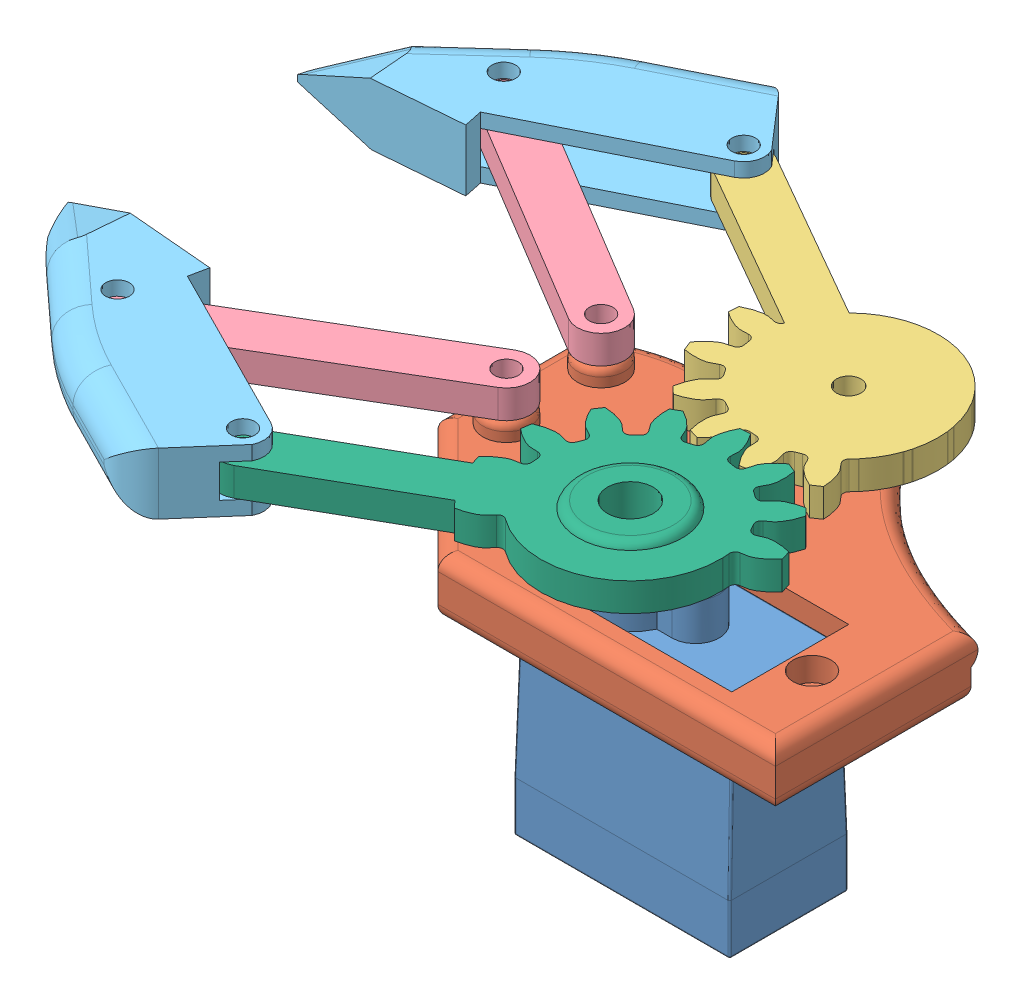
SolidWorks assembly GripperAssemV1, configuration Default. Lengths in mm.
Overall size (86.94 31.5 72.29).
8 component instances, 6 part files, 19 mates.
Components (placement in the parent):
- Part1-1: Part1 [Default] at (2.8598 15.8035 31.9584) size (32.1 26.81 12.5)
- BaseV4Part1-1: BaseV4Part1 [Default] at (7.8348 24.1035 14.5584) x (0 0 1) z (-1 0 0) size (38.46 8 48.6)
- RightGearPart2-1: RightGearPart2 [Default] at (13.6898 28.6035 -7.4143) x (0.4976 0 -0.867406) z (-0.867406 0 -0.4976) size (22.37 3 44.56)
- ShortHandPart4-1: ShortHandPart4 [Default] at (-49.9817 26.6035 -19.7668) x (0.514522 0 -0.857477) z (0.857477 0 0.514522) size (5 3 35)
- ShortHandPart4-2: ShortHandPart4 [Default] at (7.7756 26.6035 14.3423) x (0.509964 0 0.860195) z (-0.860195 0 0.509964) size (5 3 35)
- GripperHeadV4Part5-1: GripperHeadV4Part5 [Default] at (-14.2358 27.4535 -10.8856) x (-0.447199 0 -0.894435) z (0 1 0) size (13.93 38 6.5)
- ServoGearPart3-1: ServoGearPart3 [Default] at (2.1903 26.4035 16.5668) x (0.495746 0 0.868468) z (-0.868468 0 0.495746) size (22.59 3.7 45.43)
- GripperHeadV4Part5-2: GripperHeadV4Part5 [Default] at (-14.3385 27.8535 39.9593) x (-0.450943 0 0.892553) z (0 -1 0) size (13.93 38 6.5)
Mates (geometry in assembly coordinates):
- Coincident12: coincident: plane of Part1-1 through (-1.9402 18.1035 19.8084) normal (0 1 0); plane of BaseV4Part1-1 through (7.8348 18.1035 14.5584) normal (0 -1 0)
- Concentric5: concentric: circle of Part1-1; circle of BaseV4Part1-1
- Parallel11: parallel: plane of Part1-1 through (30.1598 22.2035 31.9584) normal (0 0 1); plane of BaseV4Part1-1 through (2.6548 21.1035 32.2384) normal (0 0 -1)
- Concentric14: concentric: cylinder of BaseV4Part1-1 through (8.8348 24.1035 3.0584) axis (0 1 0) radius 1.3; cylinder of RightGearPart2-1 through (8.8348 29.1035 3.0584) axis (0 -1 0) radius 1.3
- Coincident15: coincident: circle of BaseV4Part1-1; plane of RightGearPart2-1 through (-17.1874 26.1035 -11.8696) normal (0 -1 0)
- Concentric15: concentric: cylinder of BaseV4Part1-1 through (-10.8275 18.1035 9.5584) axis (0 1 0) radius 1.25; cylinder of ShortHandPart4-1 through (-10.8275 29.1035 9.5584) axis (0 -1 0) radius 1.25
- Coincident16: coincident: circle of BaseV4Part1-1; plane of ShortHandPart4-1 through (-10.8275 26.1035 9.5584) normal (0 -1 0)
- Concentric17: concentric: cylinder of BaseV4Part1-1 through (-10.8275 18.1035 19.5584) axis (0 1 0) radius 1.25; cylinder of ShortHandPart4-2 through (-10.8275 29.1035 19.5584) axis (0 -1 0) radius 1.25
- Coincident17: coincident: circle of BaseV4Part1-1; plane of ShortHandPart4-2 through (-36.6334 26.1035 34.8574) normal (0 -1 0)
- Concentric18: concentric: cylinder of RightGearPart2-1 through (-17.1874 26.1035 -11.8696) axis (0 1 0) radius 1.25; cylinder of GripperHeadV4Part5-1 through (-17.1874 24.2035 -11.8696) axis (0 1 0) radius 1.25
- Distance3: distance = 0.1 mm: plane of RightGearPart2-1 through (-17.1874 29.1035 -11.8696) normal (0 1 0); plane of GripperHeadV4Part5-1 through (-14.2358 29.2035 -10.8856) normal (0 -1 0)
- Concentric19: concentric: cylinder of ShortHandPart4-1 through (-36.5518 29.1035 -5.8772) axis (0 -1 0) radius 1.25; cylinder of GripperHeadV4Part5-1 through (-36.5518 24.2035 -5.8772) axis (0 1 0) radius 1.25
- Distance4: distance = 0.1 mm: plane of ShortHandPart4-1 through (-10.8275 29.1035 9.5584) normal (0 1 0); plane of GripperHeadV4Part5-1 through (-14.2358 29.2035 -10.8856) normal (0 -1 0)
- Concentric20: concentric: circle of Part1-1; circle of ServoGearPart3-1
- Coincident18: coincident: plane of Part1-1 through (15.6598 26.4035 26.0584) normal (0 1 0); plane of ServoGearPart3-1 through (-17.2942 26.4035 40.9308) normal (0 -1 0)
- Concentric21: concentric: cylinder of ServoGearPart3-1 through (-17.2942 26.4035 40.9308) axis (0 1 0) radius 1.25; cylinder of GripperHeadV4Part5-2 through (-17.2942 31.1035 40.9308) axis (0 -1 0) radius 1.25
- Distance5: distance = 0.2 mm: plane of ServoGearPart3-1 through (-17.2942 29.4035 40.9308) normal (0 1 0); plane of GripperHeadV4Part5-2 through (-14.3385 29.6035 39.9593) normal (0 -1 0)
- Concentric22: concentric: cylinder of ShortHandPart4-2 through (-36.6334 29.1035 34.8574) axis (0 -1 0) radius 1.25; cylinder of GripperHeadV4Part5-2 through (-36.6334 31.1035 34.8574) axis (0 -1 0) radius 1.25
- Distance6: distance = 0.2 mm: plane of ShortHandPart4-2 through (-36.6334 29.1035 34.8574) normal (0 1 0); plane of GripperHeadV4Part5-2 through (-14.3385 29.6035 39.9593) normal (0 -1 0)
